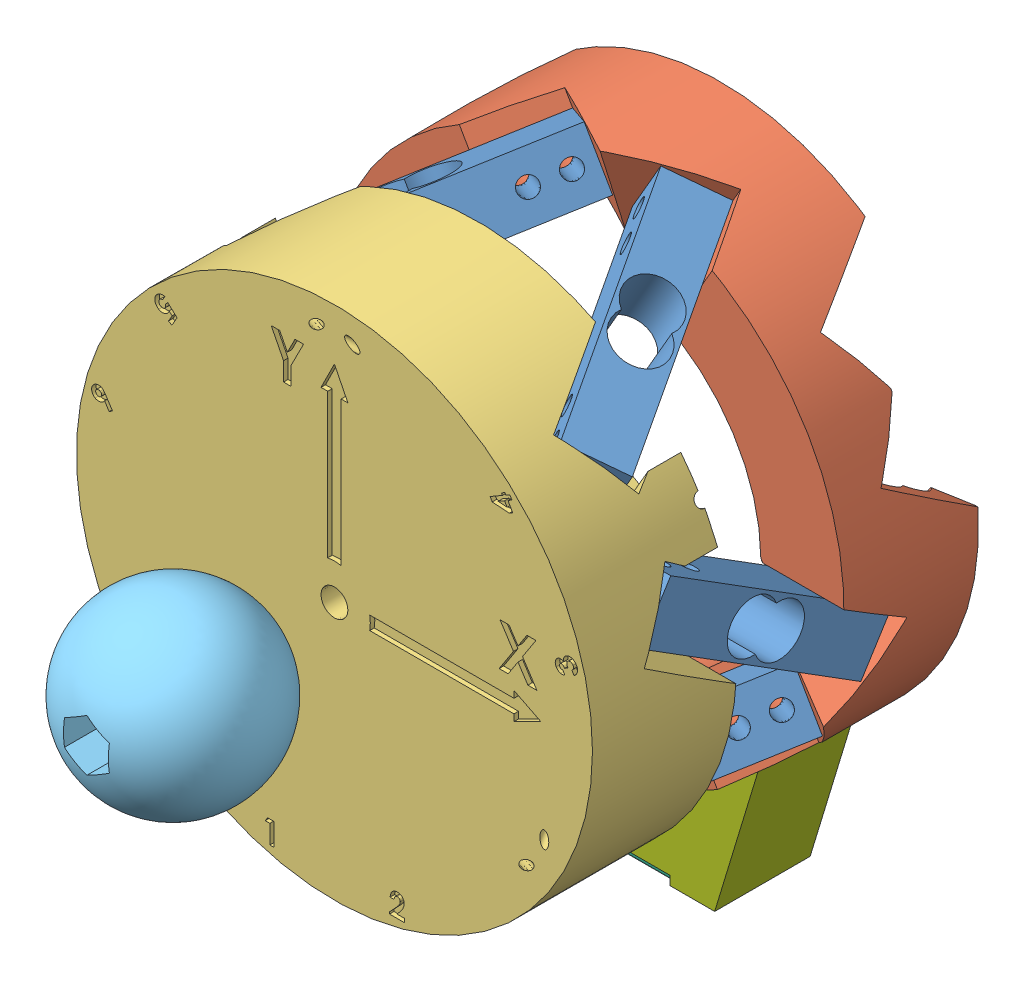
SolidWorks assembly Capteur 6 axes V5, configuration Défaut. Lengths in mm.
Overall size (115 143.4 141.36).
13 component instances, 7 part files, 30 mates.
Components (placement in the parent):
- Cellule_2kg-1: Cellule_2kg [Défaut] at (46.7654 0 43) x (1 0 0) z (0 -0.531768 -0.84689) size (12.7 12.7 58)
- Cellule_2kg-2: Cellule_2kg [Défaut] at (23.3827 40.5 43) x (0.5 0.866025 0) z (0.460525 -0.265884 0.84689) size (12.7 12.7 58)
- Cellule_2kg-3: Cellule_2kg [Défaut] at (-23.3827 40.5 43) x (0.5 -0.866025 0) z (-0.460525 -0.265884 0.84689) size (12.7 12.7 58)
- Cellule_2kg-4: Cellule_2kg [Défaut] at (-46.7654 0 43) x (1 0 0) z (0 -0.531768 -0.84689) size (12.7 12.7 58)
- Cellule_2kg-5: Cellule_2kg [Défaut] at (-23.3827 -40.5 43) x (0.5 0.866025 0) z (0.460525 -0.265884 0.84689) size (12.7 12.7 58)
- Cellule_2kg-6: Cellule_2kg [Défaut] at (23.3827 -40.5 43) x (0.5 -0.866025 0) z (-0.460525 -0.265884 0.84689) size (12.7 12.7 58)
- Bâti-1: Bâti [Défaut] at origin size (115 115 30)
- Socle V5-1: Socle V5 [Défaut] at origin size (115 115 32.11)
- hex thin nut chamfered gradeab_iso-1: hex thin nut chamfered gradeab_iso [Hexagon Thin Nut ISO - 4035 - M6 - N] at (0 0 79) size (10 11.55 3.2)
- Poignée-1: Poignée [Défaut] at (0 0 122) x (1 0 0) z (0 -1 0) size (40 35.36 40)
- VGA PORT-1: VGA PORT [По умолчанию] at (0 -80 12) x (-1 0 0) z (0 1 0) size (30.8 16.47 13.4)
- BoitierConnecteur-1: BoitierConnecteur [Défaut] at origin size (60 32.95 21.27)
- Boitier_electronique^Capteur 6 axes V5-1: Boitier_electronique^Capteur 6 axes V5 [Défaut] at origin (suppressed, hidden, virtual)
Mates (geometry in assembly coordinates):
- Coïncidente1: coincident anti-aligned: line of Cellule_2kg-1 through (46.7654 17.2559 70.4816) axis (0 -0.531768 -0.84689); line of assembly
- Coïncidente2: coincident: point of Cellule_2kg-1; plane of assembly
- Coïncidente3: coincident anti-aligned: line of Cellule_2kg-2 through (8.4387 49.1279 15.5184) axis (0.460525 -0.265884 0.84689); line of assembly
- Coïncidente4: coincident: point of Cellule_2kg-2; plane of assembly
- Coïncidente5: coincident aligned: line of Cellule_2kg-3 through (-8.4387 49.1279 15.5184) axis (-0.460525 -0.265884 0.84689); line of assembly
- Coïncidente6: coincident: point of Cellule_2kg-3; plane of assembly
- Coïncidente7: coincident aligned: line of Cellule_2kg-4 through (-46.7654 17.2559 70.4816) axis (0 -0.531768 -0.84689); line of assembly
- Coïncidente8: coincident: point of Cellule_2kg-4; plane of assembly
- Coïncidente9: coincident aligned: line of Cellule_2kg-5 through (-38.3267 -31.8721 15.5184) axis (0.460525 -0.265884 0.84689); line of assembly
- Coïncidente10: coincident: point of Cellule_2kg-5; plane of assembly
- Coïncidente11: coincident anti-aligned: line of Cellule_2kg-6 through (38.3267 -31.8721 15.5184) axis (-0.460525 -0.265884 0.84689); line of assembly
- Coïncidente12: coincident: point of Cellule_2kg-6; plane of assembly
- Coïncidente15: coincident: line of Cellule_2kg-1 through (57.4904 0 43) axis (-1 0 0); point of assembly
- Coïncidente16: coincident: line of Cellule_2kg-2 through (28.7452 49.7881 43) axis (-0.5 -0.866025 0); point of assembly
- Coïncidente17: coincident: line of Cellule_2kg-3 through (-18.0202 31.2119 43) axis (-0.5 0.866025 0); point of assembly
- Coïncidente18: coincident: line of Cellule_2kg-4 through (-36.0404 0 43) axis (-1 0 0); point of assembly
- Coïncidente19: coincident: line of Cellule_2kg-5 through (-18.0202 -31.2119 43) axis (-0.5 -0.866025 0); point of assembly
- Coïncidente20: coincident: line of Cellule_2kg-6 through (28.7452 -49.7881 43) axis (-0.5 0.866025 0); point of assembly
- Coïncidente21: coordinate: point of Bâti-1; point of Socle V5-1
- Coaxiale1: concentric aligned: cylinder of Socle V5-1 through (0 0 74) axis (0 0 1) radius 3; cylinder of hex thin nut chamfered gradeab_iso-1 through (0 0 75.8) axis (0 0 1) radius 2.5
- Coïncidente28: coincident aligned: plane of hex thin nut chamfered gradeab_iso-1 through (0 0 79) normal (0 1 0); plane of assembly through (0 0 0) normal (0 1 0)
- Coïncidente29: coincident anti-aligned: plane of Socle V5-1 through (0 0 79) normal (0 0 -1); plane of hex thin nut chamfered gradeab_iso-1 through (0 5.7735 79) normal (0 0 1)
- Coïncidente31: coordinate: unknown of ?
- Coaxiale2: concentric aligned: cylinder of Socle V5-1 through (0 0 74) axis (0 0 1) radius 3; cylinder of Poignée-1 through (0 0 102) axis (0 0 1) radius 3
- Distance1: distance = 20 mm anti-aligned: plane of Socle V5-1 through (0 0 86) normal (0 0 1); plane of Poignée-1 through (31.7269 -89.7354 106) normal (0 0 -1)
- Coïncidente32: coincident anti-aligned: plane of VGA PORT-1; plane of assembly through (0 0 0) normal (1 0 0)
- Distance2: distance = 12 mm aligned: plane of VGA PORT-1; plane of assembly through (0 0 0) normal (0 0 1)
- Distance3: distance = 80 mm aligned: plane of VGA PORT-1 through (0 -80 12) normal (0 1 0); plane of assembly through (0 0 0) normal (0 1 0)
- Coïncidente42: coincident anti-aligned: plane of ?; plane of assembly through (0 0 0) normal (1 0 0)
- Distance7: distance = 18 mm aligned: plane of ? through (0 -187.6392 18) normal (0 0 -1); plane of Bâti-1 through (0 0 0) normal (0 0 -1)
